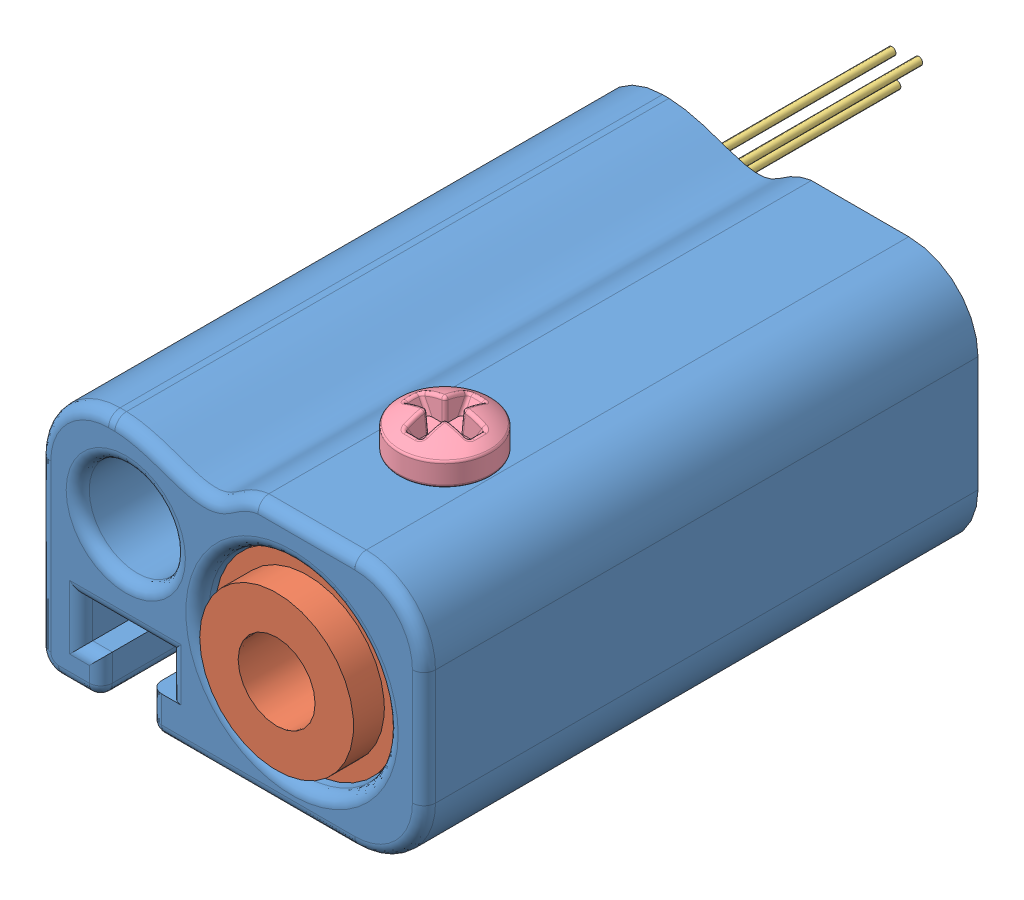
SolidWorks assembly Laser range finder assembly, configuration Default. Lengths in mm.
Overall size (25 18.9 51.82).
4 component instances, 4 part files, 4 mates.
Components (placement in the parent):
- Laser Range Finder-1: Laser Range Finder [Default] at (-0.2429 7.7548 -5.1403) size (25 17.34 36.09)
- Laser pointer-1: Laser pointer [Default] at (16.1821 15.6798 -1.1403) size (12 12 33)
- OP805-1: OP805 [Default] at (5.3821 18.6298 -5.1602) x (0.823482 -0.567342 0) z (0 0 1) size (5.5 5.5 20.8)
- Screw UNI8112_M3-1: Screw UNI8112_M3 [UNI8112_M3x5] at (17.2423 24.2548 21.9879) x (1 0 0) z (0 -1 0) size (6 6 7.4)
Mates (geometry in assembly coordinates):
- Coincident3: coincident anti-aligned: plane of Laser Range Finder-1 through (16.1821 15.6798 -1.1403) normal (0 0 1); plane of Laser pointer-1 through (16.1821 15.6798 -1.1403) normal (0 0 -1)
- Concentric1: concentric anti-aligned: cylinder of Laser Range Finder-1 through (16.1821 15.6798 -1.1403) axis (0 0 1) radius 6.15; cylinder of Laser pointer-1 through (16.1821 15.6798 29.8597) axis (0 0 -1) radius 6
- Concentric4: concentric anti-aligned: circle of Laser Range Finder-1; circle of OP805-1
- Coincident4: coincident anti-aligned: plane of Laser Range Finder-1 through (-0.2429 24.2548 30.8597) normal (0 1 0); plane of Screw UNI8112_M3-1 through (17.2423 24.2548 21.9879) normal (0 -1 0)
